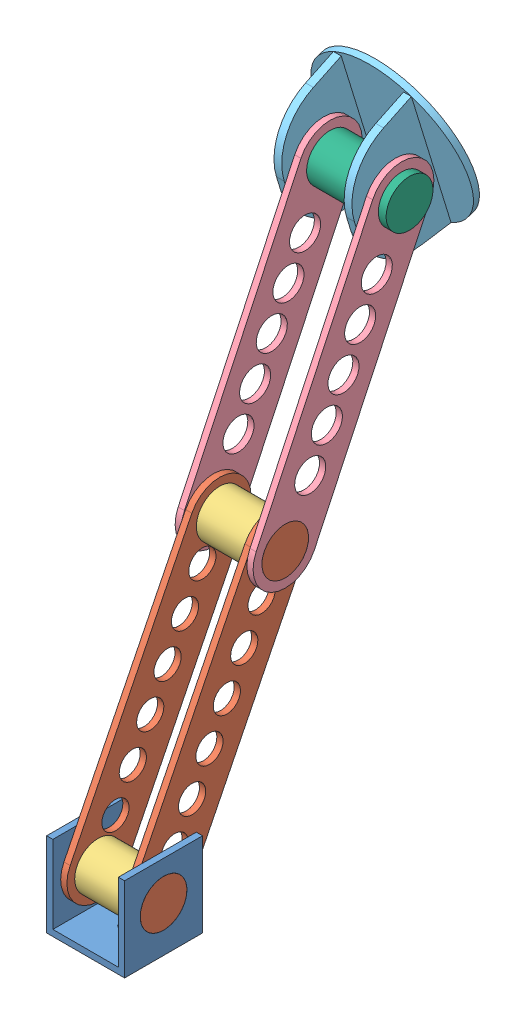
SolidWorks assembly forearm assembly, configuration Default. Lengths in mm.
Overall size (101.6 406.61 225.54).
9 component instances, 6 part files, 18 mates.
Components (placement in the parent):
- wrist-1: wrist [Default] at (33.0519 22.48 39.6573) size (50.8 54.86 50.8)
- forearm linkage-1: forearm linkage [Default] at (50.3239 51.944 39.6573) x (1 0 0) z (0 -0.895072 0.445921) size (8.13 40.64 218.44)
- forearm linkage-2: forearm linkage [Default] at (15.7799 51.944 39.6573) x (-1 0 0) z (0 -0.895072 0.445921) size (8.13 40.64 218.44)
- wrist spacer-1: wrist spacer [Default] at (15.7799 51.944 39.6573) x (0 0 -1) z (1 0 0) size (30.48 30.48 34.54)
- base arm linkage-1: base arm linkage [Default] at (7.6519 371.8686 -115.5378) x (0 -0.904279 0.426942) z (0 0.426942 0.904279) size (219.71 4.06 41.91)
- base arm linkage-2: base arm linkage [Default] at (58.4519 211.0878 -39.6275) x (0 0.904279 -0.426942) z (0 0.426942 0.904279) size (219.71 4.06 41.91)
- wrist spacer-2: wrist spacer [Default] at (15.7799 211.0878 -39.6275) x (0 0 -1) z (1 0 0) size (30.48 30.48 34.54)
- arm base-1: arm base [Default] at (27.9719 380.5291 -143.7002) x (0 -0.955826 -0.293933) z (-1 0 0) size (101.6 54.86 101.6)
- base axle-1: base axle [Default] at (2.5719 371.8686 -115.5378) x (0 -0.999855 -0.01702) z (0 -0.01702 0.999855) size (30.48 60.96 30.48)
Mates (geometry in assembly coordinates):
- Coincident1: coincident anti-aligned: plane of wrist-1 through (11.7159 77.344 14.2573) normal (1 0 0); plane of forearm linkage-2 through (11.7159 51.944 39.6573) normal (-1 0 0)
- Coincident2: coincident aligned: circle of wrist-1; plane of forearm linkage-1 through (54.3879 51.944 39.6573) normal (1 0 0)
- Coincident3: coincident aligned: plane of forearm linkage-1 through (54.3879 61.0051 57.8452) normal (0 0.445921 0.895072); plane of forearm linkage-2 through (11.7159 61.0051 57.8452) normal (0 0.445921 0.895072)
- Concentric1: concentric anti-aligned: cylinder of forearm linkage-1 through (54.3879 51.944 39.6573) axis (-1 0 0) radius 20.32; cylinder of forearm linkage-2 through (11.7159 51.944 39.6573) axis (1 0 0) radius 20.32
- Concentric2: concentric anti-aligned: cylinder of wrist-1 through (7.6519 51.944 39.6573) axis (1 0 0) radius 15.24; cylinder of forearm linkage-1 through (58.4519 51.944 39.6573) axis (-1 0 0) radius 15.24
- Coincident4: coincident anti-aligned: plane of forearm linkage-2 through (15.7799 51.944 39.6573) normal (1 0 0); plane of wrist spacer-1 through (15.7799 51.944 39.6573) normal (-1 0 0)
- Concentric3: concentric anti-aligned: cylinder of forearm linkage-2 through (11.7159 51.944 39.6573) axis (1 0 0) radius 20.32; cylinder of wrist spacer-1 through (50.3239 51.944 39.6573) axis (-1 0 0) radius 15.24
- Coincident5: coincident anti-aligned: plane of forearm linkage-1 through (54.3879 51.944 39.6573) normal (1 0 0); plane of base arm linkage-2 through (54.3879 211.0878 -39.6275) normal (-1 0 0)
- Coincident6: coincident anti-aligned: plane of forearm linkage-2 through (11.7159 51.944 39.6573) normal (-1 0 0); plane of base arm linkage-1 through (11.7159 371.8686 -115.5378) normal (1 0 0)
- Concentric4: concentric anti-aligned: cylinder of base arm linkage-1 through (11.7159 211.0878 -39.6275) axis (-1 0 0) radius 15.24; cylinder of base arm linkage-2 through (54.3879 211.0878 -39.6275) axis (1 0 0) radius 15.24
- Concentric5: concentric anti-aligned: cylinder of forearm linkage-2 through (7.6519 211.0878 -39.6275) axis (1 0 0) radius 15.24; cylinder of base arm linkage-1 through (11.7159 211.0878 -39.6275) axis (-1 0 0) radius 15.24
- Coincident7: coincident aligned: plane of base arm linkage-1 through (11.7159 362.9221 -134.4869) normal (0 -0.426942 -0.904279); plane of base arm linkage-2 through (54.3879 202.1413 -58.5767) normal (0 -0.426942 -0.904279)
- Coincident8: coincident anti-aligned: plane of forearm linkage-2 through (15.7799 51.944 39.6573) normal (1 0 0); plane of wrist spacer-2 through (15.7799 211.0878 -39.6275) normal (-1 0 0)
- Concentric6: concentric aligned: cylinder of base arm linkage-1 through (11.7159 211.0878 -39.6275) axis (-1 0 0) radius 20.955; cylinder of wrist spacer-2 through (50.3239 211.0878 -39.6275) axis (-1 0 0) radius 15.24
- Coincident9: coincident anti-aligned: plane of base arm linkage-1 through (7.6519 371.8686 -115.5378) normal (-1 0 0); plane of arm base-1 through (7.6519 364.4028 -91.2598) normal (1 0 0)
- Concentric7: concentric anti-aligned: cylinder of base arm linkage-1 through (11.7159 371.8686 -115.5378) axis (-1 0 0) radius 15.24; cylinder of arm base-1 through (-22.8281 371.8686 -115.5378) axis (1 0 0) radius 15.24
- Concentric8: concentric anti-aligned: cylinder of arm base-1 through (-22.8281 371.8686 -115.5378) axis (1 0 0) radius 15.24; cylinder of base axle-1 through (63.5319 371.8686 -115.5378) axis (-1 0 0) radius 15.24
- Coincident10: coincident aligned: plane of arm base-1 through (2.5719 364.4028 -91.2598) normal (-1 0 0); plane of base axle-1 through (2.5719 371.8686 -115.5378) normal (-1 0 0)
